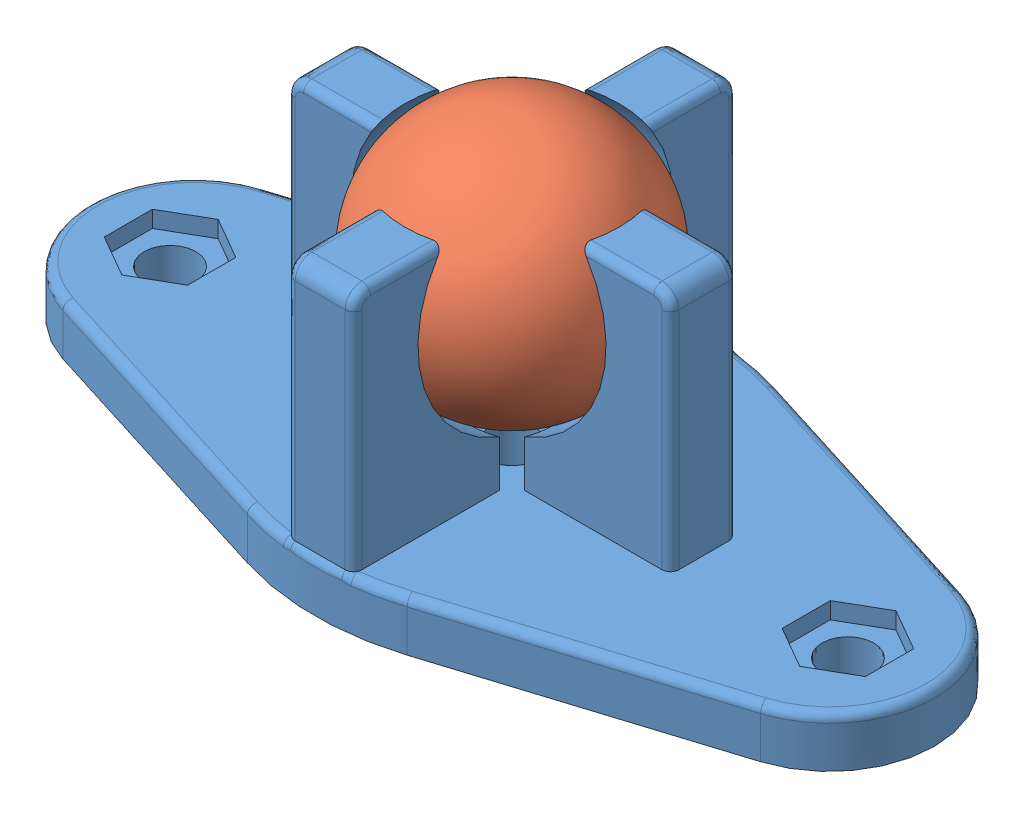
SolidWorks assembly W420 Universal Steel Ball Caster, configuration Default. Lengths in mm.
Overall size (50.67 20.4 23.62).
2 component instances, 2 part files, 2 mates.
Components (placement in the parent):
- plastic stand-1: plastic stand [Default] at (18.2421 19.7342 46.6095) x (1 0 0) z (0 1 0) size (50.67 23.62 17.5)
- ball-1: ball [Default] at (18.2421 32.6342 46.6095) size (15 15 15)
Mates (geometry in assembly coordinates):
- Concentric2: concentric anti-aligned: circle of support plastique-1; circle of ball-1
- Coincident1: coincident anti-aligned: line of support plastique-1 through (18.2421 24.7342 46.6095) axis (0 1 0); line of ball-1 through (18.2421 40.1342 46.6095) axis (0 -1 0)
